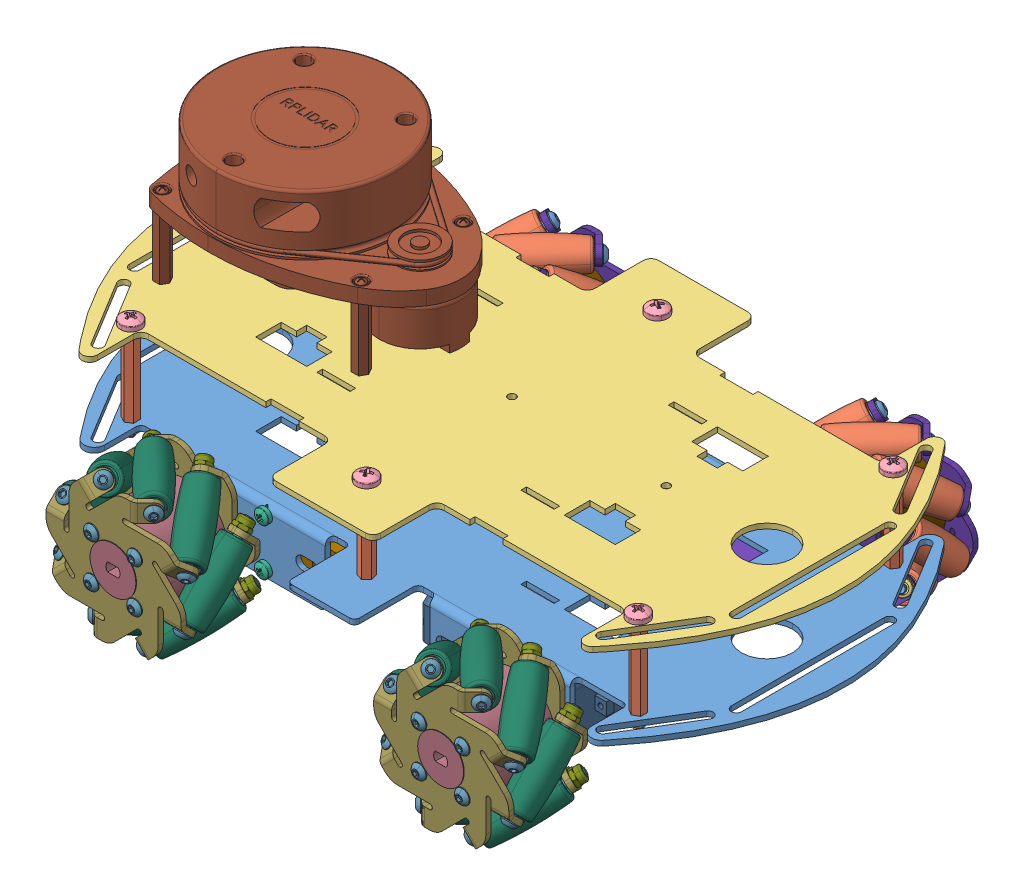
SolidWorks assembly mecanum, configuration Default. Lengths in mm.
Overall size (368.82 154.76 256.48).
187 component instances, 21 part files, 10 mates.
Components (placement in the parent):
- chassis.STEP-1: chassis.STEP [Default] at origin size (318.42 61.29 150)
  - chassis.STEP.STEP-1: chassis.STEP.STEP [Default] at origin size (318.42 61.29 150)
    - bottom chassis.STEP.STEP-1: bottom chassis.STEP.STEP [Default] at (-199.6129 0 0) x (1 0 0) z (0 0 -1) size (314.81 25.02 150)
    - supporting hexagon pillar.STEP.STEP-1: supporting hexagon pillar.STEP.STEP [Default] at (-299.1129 2 50) x (0.997179 0 -0.075054) z (0.075054 0 0.997179) size (4.8 36 5.42)
    - Copy of top chasis^chassis.STEP.STEP-1: Copy of top chasis^chassis.STEP.STEP [Default] at (-199.6129 32 0) size (318.42 2 150)
    - supporting hexagon pillar.STEP.STEP-2: supporting hexagon pillar.STEP.STEP [Default] at (-100.1129 2 50) x (0.482568 0 -0.875858) z (0.875858 0 0.482568) size (4.8 36 5.42)
    - supporting hexagon pillar.STEP.STEP-3: supporting hexagon pillar.STEP.STEP [Default] at (-100.1129 2 -50) x (0.886073 0 -0.463545) z (0.463545 0 0.886073) size (4.8 36 5.42)
    - supporting hexagon pillar.STEP.STEP-4: supporting hexagon pillar.STEP.STEP [Default] at (-299.1129 2 -50) x (0.482568 0 -0.875858) z (0.875858 0 0.482568) size (4.8 36 5.42)
    - pan head cross recess screw_iso_ISO 7045 - M4 x 5 - Z - 5N.STEP.STEP-1: pan head cross recess screw_iso_ISO 7045 - M4 x 5 - Z - 5N.STEP.STEP [Default] at (-100.1129 37.1 -50) x (0 -1 0) z (0.075054 0 0.997179) size (8.02 8 8)
    - pan head cross recess screw_iso_ISO 7045 - M4 x 5 - Z - 5N.STEP.STEP-2: pan head cross recess screw_iso_ISO 7045 - M4 x 5 - Z - 5N.STEP.STEP [Default] at (-100.1129 37.1 50) x (0 -1 0) z (0.075054 0 0.997179) size (8.02 8 8)
    - pan head cross recess screw_iso_ISO 7045 - M4 x 5 - Z - 5N.STEP.STEP-3: pan head cross recess screw_iso_ISO 7045 - M4 x 5 - Z - 5N.STEP.STEP [Default] at (-299.1129 37.1 -50) x (0 -1 0) z (0.075054 0 0.997179) size (8.02 8 8)
    - pan head cross recess screw_iso_ISO 7045 - M4 x 5 - Z - 5N.STEP.STEP-4: pan head cross recess screw_iso_ISO 7045 - M4 x 5 - Z - 5N.STEP.STEP [Default] at (-299.1129 37.1 50) x (0 -1 0) z (0.075054 0 0.997179) size (8.02 8 8)
    - hexagon thin nut (ch)_is_IS 1364-4 - M3-N.STEP.STEP-1: hexagon thin nut (ch)_is_IS 1364-4 - M3-N.STEP.STEP [Default] at (-299.1129 -1.8 -50) x (0.997179 0 -0.075054) z (0 -1 0) size (6.36 6.38 1.82)
    - hexagon thin nut (ch)_is_IS 1364-4 - M3-N.STEP.STEP-2: hexagon thin nut (ch)_is_IS 1364-4 - M3-N.STEP.STEP [Default] at (-299.1129 -1.8 50) x (0.997179 0 -0.075054) z (0 -1 0) size (6.36 6.38 1.82)
    - hexagon thin nut (ch)_is_IS 1364-4 - M3-N.STEP.STEP-3: hexagon thin nut (ch)_is_IS 1364-4 - M3-N.STEP.STEP [Default] at (-100.1129 -1.8 50) x (0.997179 0 -0.075054) z (0 -1 0) size (6.36 6.38 1.82)
    - hexagon thin nut (ch)_is_IS 1364-4 - M3-N.STEP.STEP-4: hexagon thin nut (ch)_is_IS 1364-4 - M3-N.STEP.STEP [Default] at (-100.1129 -1.8 -50) x (0.997179 0 -0.075054) z (0 -1 0) size (6.36 6.38 1.82)
    - pan head cross recess screw_iso_ISO 7045 - M3 x 30 - Z - 30S.STEP.STEP-1: pan head cross recess screw_iso_ISO 7045 - M3 x 30 - Z - 30S.STEP.STEP [Default] at (-155.6129 -20.0527 -55.1366) x (0 0 1) z (-0.913722 -0.40634 0) size (32.35 5.6 5.6)
    - pan head cross recess screw_iso_ISO 7045 - M3 x 30 - Z - 30S.STEP.STEP-2: pan head cross recess screw_iso_ISO 7045 - M3 x 30 - Z - 30S.STEP.STEP [Default] at (-155.6129 -1.6927 -55.1366) x (0 0 1) z (-0.913722 -0.40634 0) size (32.35 5.6 5.6)
    - pan head cross recess screw_iso_ISO 7045 - M3 x 30 - Z - 30S.STEP.STEP-3: pan head cross recess screw_iso_ISO 7045 - M3 x 30 - Z - 30S.STEP.STEP [Default] at (-243.6129 -20.0527 -55.1366) x (0 0 1) z (-0.913722 -0.40634 0) size (32.35 5.6 5.6)
    - pan head cross recess screw_iso_ISO 7045 - M3 x 30 - Z - 30S.STEP.STEP-4: pan head cross recess screw_iso_ISO 7045 - M3 x 30 - Z - 30S.STEP.STEP [Default] at (-243.6129 -1.6927 -55.1366) x (0 0 1) z (-0.913722 -0.40634 0) size (32.35 5.6 5.6)
    - pan head cross recess screw_iso_ISO 7045 - M3 x 30 - Z - 30S.STEP.STEP-5: pan head cross recess screw_iso_ISO 7045 - M3 x 30 - Z - 30S.STEP.STEP [Default] at (-243.6129 -20.0527 55.1366) x (0 0 -1) z (0.924865 -0.380295 0) size (32.35 5.6 5.6)
    - pan head cross recess screw_iso_ISO 7045 - M3 x 30 - Z - 30S.STEP.STEP-6: pan head cross recess screw_iso_ISO 7045 - M3 x 30 - Z - 30S.STEP.STEP [Default] at (-243.6129 -1.6927 55.1366) x (0 0 -1) z (0.924865 -0.380295 0) size (32.35 5.6 5.6)
    - pan head cross recess screw_iso_ISO 7045 - M3 x 30 - Z - 30S.STEP.STEP-7: pan head cross recess screw_iso_ISO 7045 - M3 x 30 - Z - 30S.STEP.STEP [Default] at (-155.6129 -20.0527 55.1366) x (0 0 -1) z (0.924865 -0.380295 0) size (32.35 5.6 5.6)
    - pan head cross recess screw_iso_ISO 7045 - M3 x 30 - Z - 30S.STEP.STEP-8: pan head cross recess screw_iso_ISO 7045 - M3 x 30 - Z - 30S.STEP.STEP [Default] at (-155.6129 -1.6927 55.1366) x (0 0 -1) z (0.924865 -0.380295 0) size (32.35 5.6 5.6)
    - hexagon thin nut (ch)_is_IS 1364-4 - M3-N.STEP.STEP-5: hexagon thin nut (ch)_is_IS 1364-4 - M3-N.STEP.STEP [Default] at (-155.6129 -20.1883 30.4366) x (0.939963 0.341277 0) z (0 0 -1) size (6.36 6.38 1.82)
    - hexagon thin nut (ch)_is_IS 1364-4 - M3-N.STEP.STEP-6: hexagon thin nut (ch)_is_IS 1364-4 - M3-N.STEP.STEP [Default] at (-155.6129 -1.6883 30.4366) x (0.939963 0.341277 0) z (0 0 -1) size (6.36 6.38 1.82)
    - hexagon thin nut (ch)_is_IS 1364-4 - M3-N.STEP.STEP-7: hexagon thin nut (ch)_is_IS 1364-4 - M3-N.STEP.STEP [Default] at (-243.6129 -20.057 30.4366) x (0.939963 0.341277 0) z (0 0 -1) size (6.36 6.38 1.82)
    - hexagon thin nut (ch)_is_IS 1364-4 - M3-N.STEP.STEP-8: hexagon thin nut (ch)_is_IS 1364-4 - M3-N.STEP.STEP [Default] at (-243.6129 -1.557 30.4366) x (0.939963 0.341277 0) z (0 0 -1) size (6.36 6.38 1.82)
    - hexagon thin nut (ch)_is_IS 1364-4 - M3-N.STEP.STEP-9: hexagon thin nut (ch)_is_IS 1364-4 - M3-N.STEP.STEP [Default] at (-243.6129 -20.1883 -30.4366) size (6.36 6.38 1.82)
    - hexagon thin nut (ch)_is_IS 1364-4 - M3-N.STEP.STEP-10: hexagon thin nut (ch)_is_IS 1364-4 - M3-N.STEP.STEP [Default] at (-243.6129 -1.6883 -30.4366) size (6.36 6.38 1.82)
    - hexagon thin nut (ch)_is_IS 1364-4 - M3-N.STEP.STEP-11: hexagon thin nut (ch)_is_IS 1364-4 - M3-N.STEP.STEP [Default] at (-155.6129 -20.057 -30.4366) size (6.36 6.38 1.82)
    - hexagon thin nut (ch)_is_IS 1364-4 - M3-N.STEP.STEP-12: hexagon thin nut (ch)_is_IS 1364-4 - M3-N.STEP.STEP [Default] at (-155.6129 -1.557 -30.4366) size (6.36 6.38 1.82)
    - supporting hexagon pillar.STEP.STEP-5: supporting hexagon pillar.STEP.STEP [Default] at (-199.6129 2 -57) x (0.376997 0 -0.926214) z (0.926214 0 0.376997) size (4.8 36 5.42)
    - supporting hexagon pillar.STEP.STEP-6: supporting hexagon pillar.STEP.STEP [Default] at (-199.6129 2 57) x (-0.715077 0 -0.699046) z (0.699046 0 -0.715077) size (4.8 36 5.42)
    - hexagon thin nut (ch)_is_IS 1364-4 - M3-N.STEP.STEP-13: hexagon thin nut (ch)_is_IS 1364-4 - M3-N.STEP.STEP [Default] at (-199.6129 -1.8 57) x (0.981594 0 -0.190977) z (0 -1 0) size (6.36 6.38 1.82)
    - hexagon thin nut (ch)_is_IS 1364-4 - M3-N.STEP.STEP-14: hexagon thin nut (ch)_is_IS 1364-4 - M3-N.STEP.STEP [Default] at (-199.6129 -1.8 -57) x (0.939935 0 -0.341353) z (0 -1 0) size (6.36 6.38 1.82)
    - pan head cross recess screw_iso_ISO 7045 - M4 x 5 - Z - 5N.STEP.STEP-5: pan head cross recess screw_iso_ISO 7045 - M4 x 5 - Z - 5N.STEP.STEP [Default] at (-199.6129 37.1 -57) x (0 -1 0) z (0.875858 0 0.482568) size (8.02 8 8)
    - pan head cross recess screw_iso_ISO 7045 - M4 x 5 - Z - 5N.STEP.STEP-6: pan head cross recess screw_iso_ISO 7045 - M4 x 5 - Z - 5N.STEP.STEP [Default] at (-199.6129 37.1 57) x (0 -1 0) z (0.463545 0 0.886073) size (8.02 8 8)
  - Motor1.step.STEP-1: Motor1.step.STEP [Default] at (-275.1129 -22.1883 -32.2366) size (66.5 22.5 38.5)
  - Motor2.step.STEP-1: Motor2.step.STEP [Default] at (-124.1129 0.443 -32.2366) x (-1 0 0) z (0 0 1) size (66.5 22.5 38.5)
  - Motor3.step.STEP-1: Motor3.step.STEP [Default] at (-275.1129 0.443 32.2366) x (1 0 0) z (0 0 -1) size (66.5 22.5 38.5)
  - Motor4.step.STEP-1: Motor4.step.STEP [Default] at (-124.1129 -22.1883 32.2366) x (-1 0 0) z (0 0 -1) size (66.5 22.5 38.5)
- rplidarA1.step-1: rplidarA1.step [Default] at (-280.1346 65.1 0.5722) size (96.17 54.6 70)
- left_forward.STEP-1: left_forward.STEP [Default] at (-233.0265 -21.1144 212.4082) x (-0.184533 -0.709257 -0.680369) z (0.944404 -0.319631 0.077057) size (70.26 72.13 71.93)
  - Mirrormecanum wheels.STEP.STEP-1: Mirrormecanum wheels.STEP.STEP [Default] at (81.7182 87.2657 -41.8289) x (0.184533 -0.27212 -0.944404) z (-0.680369 -0.728807 0.077057) size (55.02 55.02 7.58)
  - Mirrorshaft.STEP.STEP-1: Mirrorshaft.STEP.STEP [Default] at (90.9032 97.1046 -42.8692) x (-0.184533 0.27212 0.944404) z (0.680369 0.728807 -0.077057) size (32 32 31.5)
  - Mirrormecanum wheels.STEP.STEP-2: Mirrormecanum wheels.STEP.STEP [Default] at (100.0882 106.9435 -43.9095) x (-0.709257 0.628323 -0.319631) z (0.680369 0.728807 -0.077057) size (55.02 55.02 7.58)
  - Mirrorbolt.STEP.STEP-1: Mirrorbolt.STEP.STEP [Default] at (87.2167 86.0621 -16.0538) x (-0.020427 0.959636 -0.280501) z (0.96794 0.089234 0.234795) size (38.65 5.7 5.7)
  - MirrorRoller.STEP.STEP-1: MirrorRoller.STEP.STEP [Default] at (86.8493 103.3226 -21.099) x (-0.020427 0.959636 -0.280501) z (0.96794 0.089234 0.234795) size (28 12 12)
  - Mirrorbolt.STEP.STEP-2: Mirrorbolt.STEP.STEP [Default] at (86.8189 76.965 -46.8491) x (0.680369 0.728807 -0.077057) z (-0.018616 -0.087924 -0.995953) size (38.65 5.7 5.7)
  - Mirrortorque nut 08_iso_ISO 10511-M3-N.STEP.STEP-1: Mirrortorque nut 08_iso_ISO 10511-M3-N.STEP.STEP [Default] at (110.0875 101.8903 -49.4844) x (-0.185961 0.06998 -0.980062) z (-0.680369 -0.728807 0.077057) size (6.36 6.38 3.91)
  - Mirrortorque nut 08_iso_ISO 10511-M3-N.STEP.STEP-2: Mirrortorque nut 08_iso_ISO 10511-M3-N.STEP.STEP [Default] at (86.1032 120.5687 -26.214) x (0.873571 0.153587 0.461828) z (0.020427 -0.959636 0.280501) size (6.36 6.38 3.91)
  - Mirrorbolt.STEP.STEP-3: Mirrorbolt.STEP.STEP [Default] at (98.9986 73.9021 -27.0356) x (0.034198 0.965566 0.257899) z (0.950888 0.047997 -0.305791) size (38.65 5.7 5.7)
  - Mirrorbolt.STEP.STEP-4: Mirrorbolt.STEP.STEP [Default] at (101.0077 69.945 -46.7228) x (0.350609 0.707763 0.613307) z (0.657996 0.279839 -0.699094) size (38.65 5.7 5.7)
  - Mirrorbolt.STEP.STEP-5: Mirrorbolt.STEP.STEP [Default] at (92.0671 76.5089 -63.5829) x (0.743455 0.337243 0.57753) z (0.260835 0.648951 -0.714722) size (38.65 5.7 5.7)
  - Mirrorbolt.STEP.STEP-6: Mirrorbolt.STEP.STEP [Default] at (77.414 89.7486 -67.7394) x (0.982614 0.071053 0.171526) z (-0.007942 0.939111 -0.343521) size (38.65 5.7 5.7)
  - Mirrorbolt.STEP.STEP-7: Mirrorbolt.STEP.STEP [Default] at (65.632 101.9086 -56.7575) x (0.927989 0.065123 -0.366873) z (0.00911 0.980348 0.197064) size (38.65 5.7 5.7)
  - Mirrorbolt.STEP.STEP-8: Mirrorbolt.STEP.STEP [Default] at (63.6229 105.8657 -37.0704) x (0.611578 0.322927 -0.722281) z (0.302003 0.748506 0.590367) size (38.65 5.7 5.7)
  - Mirrorbolt.STEP.STEP-9: Mirrorbolt.STEP.STEP [Default] at (72.5636 99.3019 -20.2103) x (0.218732 0.693446 -0.686505) z (0.699163 0.379394 0.605995) size (38.65 5.7 5.7)
  - Mirrortorque nut 08_iso_ISO 10511-M3-N.STEP.STEP-3: Mirrortorque nut 08_iso_ISO 10511-M3-N.STEP.STEP [Default] at (99.872 108.6244 -17.6135) x (0.997731 -0.018009 -0.064876) z (-0.034198 -0.965566 -0.257899) size (6.36 6.38 3.91)
  - Mirrortorque nut 08_iso_ISO 10511-M3-N.STEP.STEP-4: Mirrortorque nut 08_iso_ISO 10511-M3-N.STEP.STEP [Default] at (113.3894 95.2906 -24.3739) x (0.804741 0.107283 -0.583851) z (-0.350609 -0.707763 -0.613307) size (6.36 6.38 3.91)
  - Mirrortorque nut 08_iso_ISO 10511-M3-N.STEP.STEP-5: Mirrortorque nut 08_iso_ISO 10511-M3-N.STEP.STEP [Default] at (118.7372 88.378 -42.5352) x (0.407653 0.456068 -0.791089) z (-0.743455 -0.337243 -0.57753) size (6.36 6.38 3.91)
  - Mirrortorque nut 08_iso_ISO 10511-M3-N.STEP.STEP-6: Mirrortorque nut 08_iso_ISO 10511-M3-N.STEP.STEP [Default] at (112.7827 91.936 -61.4588) x (0.039074 0.824034 -0.565191) z (-0.982614 -0.071053 -0.171526) size (6.36 6.38 3.91)
  - Mirrortorque nut 08_iso_ISO 10511-M3-N.STEP.STEP-7: Mirrortorque nut 08_iso_ISO 10511-M3-N.STEP.STEP [Default] at (99.0139 103.8803 -70.0593) x (-0.085085 0.99563 -0.038487) z (-0.927989 -0.065123 0.366873) size (6.36 6.38 3.91)
  - Mirrortorque nut 08_iso_ISO 10511-M3-N.STEP.STEP-8: Mirrortorque nut 08_iso_ISO 10511-M3-N.STEP.STEP [Default] at (85.4965 117.2141 -63.2989) x (0.107904 0.870338 0.480488) z (-0.611578 -0.322927 0.722281) size (6.36 6.38 3.91)
  - Mirrortorque nut 08_iso_ISO 10511-M3-N.STEP.STEP-9: Mirrortorque nut 08_iso_ISO 10511-M3-N.STEP.STEP [Default] at (80.1487 124.1267 -45.1376) x (0.504993 0.521552 0.687725) z (-0.218732 -0.693446 0.686505) size (6.36 6.38 3.91)
  - MirrorRoller.STEP.STEP-2: MirrorRoller.STEP.STEP [Default] at (99.6137 91.2692 -22.3969) x (0.034198 0.965566 0.257899) z (0.950888 0.047997 -0.305791) size (28 12 12)
  - MirrorRoller.STEP.STEP-3: MirrorRoller.STEP.STEP [Default] at (107.3139 82.6752 -35.6916) x (0.350609 0.707763 0.613307) z (0.657996 0.279839 -0.699094) size (28 12 12)
  - MirrorRoller.STEP.STEP-4: MirrorRoller.STEP.STEP [Default] at (105.4392 82.5747 -53.1951) x (0.743455 0.337243 0.57753) z (0.260835 0.648951 -0.714722) size (28 12 12)
  - MirrorRoller.STEP.STEP-5: MirrorRoller.STEP.STEP [Default] at (95.0877 91.0266 -64.6542) x (0.982614 0.071053 0.171526) z (-0.007942 0.939111 -0.343521) size (28 12 12)
  - MirrorRoller.STEP.STEP-6: MirrorRoller.STEP.STEP [Default] at (82.3233 103.0799 -63.3563) x (0.927989 0.065123 -0.366873) z (0.00911 0.980348 0.197064) size (28 12 12)
  - MirrorRoller.STEP.STEP-7: MirrorRoller.STEP.STEP [Default] at (74.6231 111.674 -50.0616) x (0.611578 0.322927 -0.722281) z (0.302003 0.748506 0.590367) size (28 12 12)
  - MirrorRoller.STEP.STEP-8: MirrorRoller.STEP.STEP [Default] at (76.4978 111.7745 -32.5581) x (0.218732 0.693446 -0.686505) z (0.699163 0.379394 0.605995) size (28 12 12)
  - Mirrorbolt.STEP.STEP-10: Mirrorbolt.STEP.STEP [Default] at (83.6873 81.5831 -30.822) x (0.680369 0.728807 -0.077057) z (0.168933 -0.258274 -0.951187) size (38.65 5.7 5.7)
  - Mirrorbolt.STEP.STEP-11: Mirrorbolt.STEP.STEP [Default] at (71.6508 92.2461 -36.2463) x (0.680369 0.728807 -0.077057) z (0.340283 -0.407278 -0.847545) size (38.65 5.7 5.7)
  - Mirrorbolt.STEP.STEP-12: Mirrorbolt.STEP.STEP [Default] at (74.7824 87.6281 -52.2734) x (0.680369 0.728807 -0.077057) z (0.481066 -0.523448 -0.703262) size (38.65 5.7 5.7)
  - Mirrortorque nut 08_iso_ISO 10511-M3-N.STEP.STEP-10: Mirrortorque nut 08_iso_ISO 10511-M3-N.STEP.STEP [Default] at (98.051 112.5533 -54.9087) x (0.533825 -0.420797 0.733458) z (-0.680369 -0.728807 0.077057) size (6.36 6.38 3.91)
  - Mirrortorque nut 08_iso_ISO 10511-M3-N.STEP.STEP-11: Mirrortorque nut 08_iso_ISO 10511-M3-N.STEP.STEP [Default] at (106.9559 106.5083 -33.4573) x (0.321016 -0.201847 0.925314) z (-0.680369 -0.728807 0.077057) size (6.36 6.38 3.91)
  - Mirrortorque nut 08_iso_ISO 10511-M3-N.STEP.STEP-12: Mirrortorque nut 08_iso_ISO 10511-M3-N.STEP.STEP [Default] at (94.9194 117.1713 -38.8817) x (0.017858 0.088626 0.995905) z (-0.680369 -0.728807 0.077057) size (6.36 6.38 3.91)
- right_forward.STEP-1: right_forward.STEP [Default] at (-233.0265 -21.1144 -212.4082) x (-0.184533 -0.709257 0.680369) z (-0.944404 0.319631 0.077057) size (70.26 72.13 71.93)
  - MirrorMirrormecanum wheels.STEP.STEP.STEP-1: MirrorMirrormecanum wheels.STEP.STEP.STEP [Default] at (81.7182 87.2657 41.8289) x (0.184533 -0.27212 0.944404) z (0.680369 0.728807 0.077057) size (55.02 55.02 7.58)
  - MirrorMirrorshaft.STEP.STEP.STEP-1: MirrorMirrorshaft.STEP.STEP.STEP [Default] at (90.9032 97.1046 42.8692) x (-0.184533 0.27212 -0.944404) z (-0.680369 -0.728807 -0.077057) size (32 32 31.5)
  - MirrorMirrormecanum wheels.STEP.STEP.STEP-2: MirrorMirrormecanum wheels.STEP.STEP.STEP [Default] at (100.0882 106.9435 43.9095) x (-0.709257 0.628323 0.319631) z (-0.680369 -0.728807 -0.077057) size (55.02 55.02 7.58)
  - MirrorMirrorbolt.STEP.STEP.STEP-1: MirrorMirrorbolt.STEP.STEP.STEP [Default] at (87.2167 86.0621 16.0538) x (-0.020427 0.959636 0.280501) z (-0.96794 -0.089234 0.234795) size (38.65 5.7 5.7)
  - MirrorMirrorRoller.STEP.STEP.STEP-1: MirrorMirrorRoller.STEP.STEP.STEP [Default] at (86.8493 103.3226 21.099) x (-0.020427 0.959636 0.280501) z (-0.96794 -0.089234 0.234795) size (28 12 12)
  - MirrorMirrorbolt.STEP.STEP.STEP-2: MirrorMirrorbolt.STEP.STEP.STEP [Default] at (86.8189 76.965 46.8491) x (0.680369 0.728807 0.077057) z (0.018616 0.087924 -0.995953) size (38.65 5.7 5.7)
  - MirrorMirrortorque nut 08_iso_ISO 10511-M3-N.STEP.STEP.STEP-1: MirrorMirrortorque nut 08_iso_ISO 10511-M3-N.STEP.STEP.STEP [Default] at (110.0875 101.8903 49.4844) x (-0.185961 0.06998 0.980062) z (0.680369 0.728807 0.077057) size (6.36 6.36 3.91)
  - MirrorMirrortorque nut 08_iso_ISO 10511-M3-N.STEP.STEP.STEP-2: MirrorMirrortorque nut 08_iso_ISO 10511-M3-N.STEP.STEP.STEP [Default] at (86.1032 120.5687 26.214) x (0.873571 0.153587 -0.461828) z (-0.020427 0.959636 0.280501) size (6.36 6.36 3.91)
  - MirrorMirrorbolt.STEP.STEP.STEP-3: MirrorMirrorbolt.STEP.STEP.STEP [Default] at (98.9986 73.9021 27.0356) x (0.034198 0.965566 -0.257899) z (-0.950888 -0.047997 -0.305791) size (38.65 5.7 5.7)
  - MirrorMirrorbolt.STEP.STEP.STEP-4: MirrorMirrorbolt.STEP.STEP.STEP [Default] at (101.0077 69.945 46.7228) x (0.350609 0.707763 -0.613307) z (-0.657996 -0.279839 -0.699094) size (38.65 5.7 5.7)
  - MirrorMirrorbolt.STEP.STEP.STEP-5: MirrorMirrorbolt.STEP.STEP.STEP [Default] at (92.0671 76.5089 63.5829) x (0.743455 0.337243 -0.57753) z (-0.260835 -0.648951 -0.714722) size (38.65 5.7 5.7)
  - MirrorMirrorbolt.STEP.STEP.STEP-6: MirrorMirrorbolt.STEP.STEP.STEP [Default] at (77.414 89.7486 67.7394) x (0.982614 0.071053 -0.171526) z (0.007942 -0.939111 -0.343521) size (38.65 5.7 5.7)
  - MirrorMirrorbolt.STEP.STEP.STEP-7: MirrorMirrorbolt.STEP.STEP.STEP [Default] at (65.632 101.9086 56.7575) x (0.927989 0.065123 0.366873) z (-0.00911 -0.980348 0.197064) size (38.65 5.7 5.7)
  - MirrorMirrorbolt.STEP.STEP.STEP-8: MirrorMirrorbolt.STEP.STEP.STEP [Default] at (63.6229 105.8657 37.0704) x (0.611578 0.322927 0.722281) z (-0.302003 -0.748506 0.590367) size (38.65 5.7 5.7)
  - MirrorMirrorbolt.STEP.STEP.STEP-9: MirrorMirrorbolt.STEP.STEP.STEP [Default] at (72.5636 99.3019 20.2103) x (0.218732 0.693446 0.686505) z (-0.699163 -0.379394 0.605995) size (38.65 5.7 5.7)
  - MirrorMirrortorque nut 08_iso_ISO 10511-M3-N.STEP.STEP.STEP-3: MirrorMirrortorque nut 08_iso_ISO 10511-M3-N.STEP.STEP.STEP [Default] at (99.872 108.6244 17.6135) x (0.997731 -0.018009 0.064876) z (0.034198 0.965566 -0.257899) size (6.36 6.36 3.91)
  - MirrorMirrortorque nut 08_iso_ISO 10511-M3-N.STEP.STEP.STEP-4: MirrorMirrortorque nut 08_iso_ISO 10511-M3-N.STEP.STEP.STEP [Default] at (113.3894 95.2906 24.3739) x (0.804741 0.107283 0.583851) z (0.350609 0.707763 -0.613307) size (6.36 6.36 3.91)
  - MirrorMirrortorque nut 08_iso_ISO 10511-M3-N.STEP.STEP.STEP-5: MirrorMirrortorque nut 08_iso_ISO 10511-M3-N.STEP.STEP.STEP [Default] at (118.7372 88.378 42.5352) x (0.407653 0.456068 0.791089) z (0.743455 0.337243 -0.57753) size (6.36 6.36 3.91)
  - MirrorMirrortorque nut 08_iso_ISO 10511-M3-N.STEP.STEP.STEP-6: MirrorMirrortorque nut 08_iso_ISO 10511-M3-N.STEP.STEP.STEP [Default] at (112.7827 91.936 61.4588) x (0.039074 0.824034 0.565191) z (0.982614 0.071053 -0.171526) size (6.36 6.36 3.91)
  - MirrorMirrortorque nut 08_iso_ISO 10511-M3-N.STEP.STEP.STEP-7: MirrorMirrortorque nut 08_iso_ISO 10511-M3-N.STEP.STEP.STEP [Default] at (99.0139 103.8803 70.0593) x (-0.085085 0.99563 0.038487) z (0.927989 0.065123 0.366873) size (6.36 6.36 3.91)
  - MirrorMirrortorque nut 08_iso_ISO 10511-M3-N.STEP.STEP.STEP-8: MirrorMirrortorque nut 08_iso_ISO 10511-M3-N.STEP.STEP.STEP [Default] at (85.4965 117.2141 63.2989) x (0.107904 0.870338 -0.480488) z (0.611578 0.322927 0.722281) size (6.36 6.36 3.91)
  - MirrorMirrortorque nut 08_iso_ISO 10511-M3-N.STEP.STEP.STEP-9: MirrorMirrortorque nut 08_iso_ISO 10511-M3-N.STEP.STEP.STEP [Default] at (80.1487 124.1267 45.1376) x (0.504993 0.521552 -0.687725) z (0.218732 0.693446 0.686505) size (6.36 6.36 3.91)
  - MirrorMirrorRoller.STEP.STEP.STEP-2: MirrorMirrorRoller.STEP.STEP.STEP [Default] at (99.6137 91.2692 22.3969) x (0.034198 0.965566 -0.257899) z (-0.950888 -0.047997 -0.305791) size (28 12 12)
  - MirrorMirrorRoller.STEP.STEP.STEP-3: MirrorMirrorRoller.STEP.STEP.STEP [Default] at (107.3139 82.6752 35.6916) x (0.350609 0.707763 -0.613307) z (-0.657996 -0.279839 -0.699094) size (28 12 12)
  - MirrorMirrorRoller.STEP.STEP.STEP-4: MirrorMirrorRoller.STEP.STEP.STEP [Default] at (105.4392 82.5747 53.1951) x (0.743455 0.337243 -0.57753) z (-0.260835 -0.648951 -0.714722) size (28 12 12)
  - MirrorMirrorRoller.STEP.STEP.STEP-5: MirrorMirrorRoller.STEP.STEP.STEP [Default] at (95.0877 91.0266 64.6542) x (0.982614 0.071053 -0.171526) z (0.007942 -0.939111 -0.343521) size (28 12 12)
  - MirrorMirrorRoller.STEP.STEP.STEP-6: MirrorMirrorRoller.STEP.STEP.STEP [Default] at (82.3233 103.0799 63.3563) x (0.927989 0.065123 0.366873) z (-0.00911 -0.980348 0.197064) size (28 12 12)
  - MirrorMirrorRoller.STEP.STEP.STEP-7: MirrorMirrorRoller.STEP.STEP.STEP [Default] at (74.6231 111.674 50.0616) x (0.611578 0.322927 0.722281) z (-0.302003 -0.748506 0.590367) size (28 12 12)
  - MirrorMirrorRoller.STEP.STEP.STEP-8: MirrorMirrorRoller.STEP.STEP.STEP [Default] at (76.4978 111.7745 32.5581) x (0.218732 0.693446 0.686505) z (-0.699163 -0.379394 0.605995) size (28 12 12)
  - MirrorMirrorbolt.STEP.STEP.STEP-10: MirrorMirrorbolt.STEP.STEP.STEP [Default] at (83.6873 81.5831 30.822) x (0.680369 0.728807 0.077057) z (-0.168933 0.258274 -0.951187) size (38.65 5.7 5.7)
  - MirrorMirrorbolt.STEP.STEP.STEP-11: MirrorMirrorbolt.STEP.STEP.STEP [Default] at (71.6508 92.2461 36.2463) x (0.680369 0.728807 0.077057) z (-0.340283 0.407278 -0.847545) size (38.65 5.7 5.7)
  - MirrorMirrorbolt.STEP.STEP.STEP-12: MirrorMirrorbolt.STEP.STEP.STEP [Default] at (74.7824 87.6281 52.2734) x (0.680369 0.728807 0.077057) z (-0.481066 0.523448 -0.703262) size (38.65 5.7 5.7)
  - MirrorMirrortorque nut 08_iso_ISO 10511-M3-N.STEP.STEP.STEP-10: MirrorMirrortorque nut 08_iso_ISO 10511-M3-N.STEP.STEP.STEP [Default] at (98.051 112.5533 54.9087) x (0.533825 -0.420797 -0.733458) z (0.680369 0.728807 0.077057) size (6.36 6.36 3.91)
  - MirrorMirrortorque nut 08_iso_ISO 10511-M3-N.STEP.STEP.STEP-11: MirrorMirrortorque nut 08_iso_ISO 10511-M3-N.STEP.STEP.STEP [Default] at (106.9559 106.5083 33.4573) x (0.321016 -0.201847 -0.925314) z (0.680369 0.728807 0.077057) size (6.36 6.36 3.91)
  - MirrorMirrortorque nut 08_iso_ISO 10511-M3-N.STEP.STEP.STEP-12: MirrorMirrortorque nut 08_iso_ISO 10511-M3-N.STEP.STEP.STEP [Default] at (94.9194 117.1713 38.8817) x (0.017858 0.088626 -0.995905) z (0.680369 0.728807 0.077057) size (6.36 6.36 3.91)
- left_back.STEP-1: left_back.STEP [Default] at (-104.5265 -21.1144 212.4082) x (-0.184533 -0.709257 -0.680369) z (0.944404 -0.319631 0.077057) size (70.26 72.13 71.93)
  - Mirrormecanum wheels.STEP.STEP-1: Mirrormecanum wheels.STEP.STEP [Default] at (81.7182 87.2657 -41.8289) x (0.184533 -0.27212 -0.944404) z (-0.680369 -0.728807 0.077057) size (55.02 55.02 7.58)
  - Mirrorshaft.STEP.STEP-1: Mirrorshaft.STEP.STEP [Default] at (90.9032 97.1046 -42.8692) x (-0.184533 0.27212 0.944404) z (0.680369 0.728807 -0.077057) size (32 32 31.5)
  - Mirrormecanum wheels.STEP.STEP-2: Mirrormecanum wheels.STEP.STEP [Default] at (100.0882 106.9435 -43.9095) x (-0.709257 0.628323 -0.319631) z (0.680369 0.728807 -0.077057) size (55.02 55.02 7.58)
  - Mirrorbolt.STEP.STEP-1: Mirrorbolt.STEP.STEP [Default] at (87.2167 86.0621 -16.0538) x (-0.020427 0.959636 -0.280501) z (0.96794 0.089234 0.234795) size (38.65 5.7 5.7)
  - MirrorRoller.STEP.STEP-1: MirrorRoller.STEP.STEP [Default] at (86.8493 103.3226 -21.099) x (-0.020427 0.959636 -0.280501) z (0.96794 0.089234 0.234795) size (28 12 12)
  - Mirrorbolt.STEP.STEP-2: Mirrorbolt.STEP.STEP [Default] at (86.8189 76.965 -46.8491) x (0.680369 0.728807 -0.077057) z (-0.018616 -0.087924 -0.995953) size (38.65 5.7 5.7)
  - Mirrortorque nut 08_iso_ISO 10511-M3-N.STEP.STEP-1: Mirrortorque nut 08_iso_ISO 10511-M3-N.STEP.STEP [Default] at (110.0875 101.8903 -49.4844) x (-0.185961 0.06998 -0.980062) z (-0.680369 -0.728807 0.077057) size (6.36 6.38 3.91)
  - Mirrortorque nut 08_iso_ISO 10511-M3-N.STEP.STEP-2: Mirrortorque nut 08_iso_ISO 10511-M3-N.STEP.STEP [Default] at (86.1032 120.5687 -26.214) x (0.873571 0.153587 0.461828) z (0.020427 -0.959636 0.280501) size (6.36 6.38 3.91)
  - Mirrorbolt.STEP.STEP-3: Mirrorbolt.STEP.STEP [Default] at (98.9986 73.9021 -27.0356) x (0.034198 0.965566 0.257899) z (0.950888 0.047997 -0.305791) size (38.65 5.7 5.7)
  - Mirrorbolt.STEP.STEP-4: Mirrorbolt.STEP.STEP [Default] at (101.0077 69.945 -46.7228) x (0.350609 0.707763 0.613307) z (0.657996 0.279839 -0.699094) size (38.65 5.7 5.7)
  - Mirrorbolt.STEP.STEP-5: Mirrorbolt.STEP.STEP [Default] at (92.0671 76.5089 -63.5829) x (0.743455 0.337243 0.57753) z (0.260835 0.648951 -0.714722) size (38.65 5.7 5.7)
  - Mirrorbolt.STEP.STEP-6: Mirrorbolt.STEP.STEP [Default] at (77.414 89.7486 -67.7394) x (0.982614 0.071053 0.171526) z (-0.007942 0.939111 -0.343521) size (38.65 5.7 5.7)
  - Mirrorbolt.STEP.STEP-7: Mirrorbolt.STEP.STEP [Default] at (65.632 101.9086 -56.7575) x (0.927989 0.065123 -0.366873) z (0.00911 0.980348 0.197064) size (38.65 5.7 5.7)
  - Mirrorbolt.STEP.STEP-8: Mirrorbolt.STEP.STEP [Default] at (63.6229 105.8657 -37.0704) x (0.611578 0.322927 -0.722281) z (0.302003 0.748506 0.590367) size (38.65 5.7 5.7)
  - Mirrorbolt.STEP.STEP-9: Mirrorbolt.STEP.STEP [Default] at (72.5636 99.3019 -20.2103) x (0.218732 0.693446 -0.686505) z (0.699163 0.379394 0.605995) size (38.65 5.7 5.7)
  - Mirrortorque nut 08_iso_ISO 10511-M3-N.STEP.STEP-3: Mirrortorque nut 08_iso_ISO 10511-M3-N.STEP.STEP [Default] at (99.872 108.6244 -17.6135) x (0.997731 -0.018009 -0.064876) z (-0.034198 -0.965566 -0.257899) size (6.36 6.38 3.91)
  - Mirrortorque nut 08_iso_ISO 10511-M3-N.STEP.STEP-4: Mirrortorque nut 08_iso_ISO 10511-M3-N.STEP.STEP [Default] at (113.3894 95.2906 -24.3739) x (0.804741 0.107283 -0.583851) z (-0.350609 -0.707763 -0.613307) size (6.36 6.38 3.91)
  - Mirrortorque nut 08_iso_ISO 10511-M3-N.STEP.STEP-5: Mirrortorque nut 08_iso_ISO 10511-M3-N.STEP.STEP [Default] at (118.7372 88.378 -42.5352) x (0.407653 0.456068 -0.791089) z (-0.743455 -0.337243 -0.57753) size (6.36 6.38 3.91)
  - Mirrortorque nut 08_iso_ISO 10511-M3-N.STEP.STEP-6: Mirrortorque nut 08_iso_ISO 10511-M3-N.STEP.STEP [Default] at (112.7827 91.936 -61.4588) x (0.039074 0.824034 -0.565191) z (-0.982614 -0.071053 -0.171526) size (6.36 6.38 3.91)
  - Mirrortorque nut 08_iso_ISO 10511-M3-N.STEP.STEP-7: Mirrortorque nut 08_iso_ISO 10511-M3-N.STEP.STEP [Default] at (99.0139 103.8803 -70.0593) x (-0.085085 0.99563 -0.038487) z (-0.927989 -0.065123 0.366873) size (6.36 6.38 3.91)
  - Mirrortorque nut 08_iso_ISO 10511-M3-N.STEP.STEP-8: Mirrortorque nut 08_iso_ISO 10511-M3-N.STEP.STEP [Default] at (85.4965 117.2141 -63.2989) x (0.107904 0.870338 0.480488) z (-0.611578 -0.322927 0.722281) size (6.36 6.38 3.91)
  - Mirrortorque nut 08_iso_ISO 10511-M3-N.STEP.STEP-9: Mirrortorque nut 08_iso_ISO 10511-M3-N.STEP.STEP [Default] at (80.1487 124.1267 -45.1376) x (0.504993 0.521552 0.687725) z (-0.218732 -0.693446 0.686505) size (6.36 6.38 3.91)
  - MirrorRoller.STEP.STEP-2: MirrorRoller.STEP.STEP [Default] at (99.6137 91.2692 -22.3969) x (0.034198 0.965566 0.257899) z (0.950888 0.047997 -0.305791) size (28 12 12)
  - MirrorRoller.STEP.STEP-3: MirrorRoller.STEP.STEP [Default] at (107.3139 82.6752 -35.6916) x (0.350609 0.707763 0.613307) z (0.657996 0.279839 -0.699094) size (28 12 12)
  - MirrorRoller.STEP.STEP-4: MirrorRoller.STEP.STEP [Default] at (105.4392 82.5747 -53.1951) x (0.743455 0.337243 0.57753) z (0.260835 0.648951 -0.714722) size (28 12 12)
  - MirrorRoller.STEP.STEP-5: MirrorRoller.STEP.STEP [Default] at (95.0877 91.0266 -64.6542) x (0.982614 0.071053 0.171526) z (-0.007942 0.939111 -0.343521) size (28 12 12)
  - MirrorRoller.STEP.STEP-6: MirrorRoller.STEP.STEP [Default] at (82.3233 103.0799 -63.3563) x (0.927989 0.065123 -0.366873) z (0.00911 0.980348 0.197064) size (28 12 12)
  - MirrorRoller.STEP.STEP-7: MirrorRoller.STEP.STEP [Default] at (74.6231 111.674 -50.0616) x (0.611578 0.322927 -0.722281) z (0.302003 0.748506 0.590367) size (28 12 12)
  - MirrorRoller.STEP.STEP-8: MirrorRoller.STEP.STEP [Default] at (76.4978 111.7745 -32.5581) x (0.218732 0.693446 -0.686505) z (0.699163 0.379394 0.605995) size (28 12 12)
  - Mirrorbolt.STEP.STEP-10: Mirrorbolt.STEP.STEP [Default] at (83.6873 81.5831 -30.822) x (0.680369 0.728807 -0.077057) z (0.168933 -0.258274 -0.951187) size (38.65 5.7 5.7)
  - Mirrorbolt.STEP.STEP-11: Mirrorbolt.STEP.STEP [Default] at (71.6508 92.2461 -36.2463) x (0.680369 0.728807 -0.077057) z (0.340283 -0.407278 -0.847545) size (38.65 5.7 5.7)
  - Mirrorbolt.STEP.STEP-12: Mirrorbolt.STEP.STEP [Default] at (74.7824 87.6281 -52.2734) x (0.680369 0.728807 -0.077057) z (0.481066 -0.523448 -0.703262) size (38.65 5.7 5.7)
  - Mirrortorque nut 08_iso_ISO 10511-M3-N.STEP.STEP-10: Mirrortorque nut 08_iso_ISO 10511-M3-N.STEP.STEP [Default] at (98.051 112.5533 -54.9087) x (0.533825 -0.420797 0.733458) z (-0.680369 -0.728807 0.077057) size (6.36 6.38 3.91)
  - Mirrortorque nut 08_iso_ISO 10511-M3-N.STEP.STEP-11: Mirrortorque nut 08_iso_ISO 10511-M3-N.STEP.STEP [Default] at (106.9559 106.5083 -33.4573) x (0.321016 -0.201847 0.925314) z (-0.680369 -0.728807 0.077057) size (6.36 6.38 3.91)
  - Mirrortorque nut 08_iso_ISO 10511-M3-N.STEP.STEP-12: Mirrortorque nut 08_iso_ISO 10511-M3-N.STEP.STEP [Default] at (94.9194 117.1713 -38.8817) x (0.017858 0.088626 0.995905) z (-0.680369 -0.728807 0.077057) size (6.36 6.38 3.91)
- right_back.STEP-1: right_back.STEP [Default] at (-104.5265 -21.1144 -212.4082) x (-0.184533 -0.709257 0.680369) z (-0.944404 0.319631 0.077057) size (70.26 72.13 71.93)
  - MirrorMirrormecanum wheels.STEP.STEP.STEP-1: MirrorMirrormecanum wheels.STEP.STEP.STEP [Default] at (81.7182 87.2657 41.8289) x (0.184533 -0.27212 0.944404) z (0.680369 0.728807 0.077057) size (55.02 55.02 7.58)
  - MirrorMirrorshaft.STEP.STEP.STEP-1: MirrorMirrorshaft.STEP.STEP.STEP [Default] at (90.9032 97.1046 42.8692) x (-0.184533 0.27212 -0.944404) z (-0.680369 -0.728807 -0.077057) size (32 32 31.5)
  - MirrorMirrormecanum wheels.STEP.STEP.STEP-2: MirrorMirrormecanum wheels.STEP.STEP.STEP [Default] at (100.0882 106.9435 43.9095) x (-0.709257 0.628323 0.319631) z (-0.680369 -0.728807 -0.077057) size (55.02 55.02 7.58)
  - MirrorMirrorbolt.STEP.STEP.STEP-1: MirrorMirrorbolt.STEP.STEP.STEP [Default] at (87.2167 86.0621 16.0538) x (-0.020427 0.959636 0.280501) z (-0.96794 -0.089234 0.234795) size (38.65 5.7 5.7)
  - MirrorMirrorRoller.STEP.STEP.STEP-1: MirrorMirrorRoller.STEP.STEP.STEP [Default] at (86.8493 103.3226 21.099) x (-0.020427 0.959636 0.280501) z (-0.96794 -0.089234 0.234795) size (28 12 12)
  - MirrorMirrorbolt.STEP.STEP.STEP-2: MirrorMirrorbolt.STEP.STEP.STEP [Default] at (86.8189 76.965 46.8491) x (0.680369 0.728807 0.077057) z (0.018616 0.087924 -0.995953) size (38.65 5.7 5.7)
  - MirrorMirrortorque nut 08_iso_ISO 10511-M3-N.STEP.STEP.STEP-1: MirrorMirrortorque nut 08_iso_ISO 10511-M3-N.STEP.STEP.STEP [Default] at (110.0875 101.8903 49.4844) x (-0.185961 0.06998 0.980062) z (0.680369 0.728807 0.077057) size (6.36 6.36 3.91)
  - MirrorMirrortorque nut 08_iso_ISO 10511-M3-N.STEP.STEP.STEP-2: MirrorMirrortorque nut 08_iso_ISO 10511-M3-N.STEP.STEP.STEP [Default] at (86.1032 120.5687 26.214) x (0.873571 0.153587 -0.461828) z (-0.020427 0.959636 0.280501) size (6.36 6.36 3.91)
  - MirrorMirrorbolt.STEP.STEP.STEP-3: MirrorMirrorbolt.STEP.STEP.STEP [Default] at (98.9986 73.9021 27.0356) x (0.034198 0.965566 -0.257899) z (-0.950888 -0.047997 -0.305791) size (38.65 5.7 5.7)
  - MirrorMirrorbolt.STEP.STEP.STEP-4: MirrorMirrorbolt.STEP.STEP.STEP [Default] at (101.0077 69.945 46.7228) x (0.350609 0.707763 -0.613307) z (-0.657996 -0.279839 -0.699094) size (38.65 5.7 5.7)
  - MirrorMirrorbolt.STEP.STEP.STEP-5: MirrorMirrorbolt.STEP.STEP.STEP [Default] at (92.0671 76.5089 63.5829) x (0.743455 0.337243 -0.57753) z (-0.260835 -0.648951 -0.714722) size (38.65 5.7 5.7)
  - MirrorMirrorbolt.STEP.STEP.STEP-6: MirrorMirrorbolt.STEP.STEP.STEP [Default] at (77.414 89.7486 67.7394) x (0.982614 0.071053 -0.171526) z (0.007942 -0.939111 -0.343521) size (38.65 5.7 5.7)
  - MirrorMirrorbolt.STEP.STEP.STEP-7: MirrorMirrorbolt.STEP.STEP.STEP [Default] at (65.632 101.9086 56.7575) x (0.927989 0.065123 0.366873) z (-0.00911 -0.980348 0.197064) size (38.65 5.7 5.7)
  - MirrorMirrorbolt.STEP.STEP.STEP-8: MirrorMirrorbolt.STEP.STEP.STEP [Default] at (63.6229 105.8657 37.0704) x (0.611578 0.322927 0.722281) z (-0.302003 -0.748506 0.590367) size (38.65 5.7 5.7)
  - MirrorMirrorbolt.STEP.STEP.STEP-9: MirrorMirrorbolt.STEP.STEP.STEP [Default] at (72.5636 99.3019 20.2103) x (0.218732 0.693446 0.686505) z (-0.699163 -0.379394 0.605995) size (38.65 5.7 5.7)
  - MirrorMirrortorque nut 08_iso_ISO 10511-M3-N.STEP.STEP.STEP-3: MirrorMirrortorque nut 08_iso_ISO 10511-M3-N.STEP.STEP.STEP [Default] at (99.872 108.6244 17.6135) x (0.997731 -0.018009 0.064876) z (0.034198 0.965566 -0.257899) size (6.36 6.36 3.91)
  - MirrorMirrortorque nut 08_iso_ISO 10511-M3-N.STEP.STEP.STEP-4: MirrorMirrortorque nut 08_iso_ISO 10511-M3-N.STEP.STEP.STEP [Default] at (113.3894 95.2906 24.3739) x (0.804741 0.107283 0.583851) z (0.350609 0.707763 -0.613307) size (6.36 6.36 3.91)
  - MirrorMirrortorque nut 08_iso_ISO 10511-M3-N.STEP.STEP.STEP-5: MirrorMirrortorque nut 08_iso_ISO 10511-M3-N.STEP.STEP.STEP [Default] at (118.7372 88.378 42.5352) x (0.407653 0.456068 0.791089) z (0.743455 0.337243 -0.57753) size (6.36 6.36 3.91)
  - MirrorMirrortorque nut 08_iso_ISO 10511-M3-N.STEP.STEP.STEP-6: MirrorMirrortorque nut 08_iso_ISO 10511-M3-N.STEP.STEP.STEP [Default] at (112.7827 91.936 61.4588) x (0.039074 0.824034 0.565191) z (0.982614 0.071053 -0.171526) size (6.36 6.36 3.91)
  - MirrorMirrortorque nut 08_iso_ISO 10511-M3-N.STEP.STEP.STEP-7: MirrorMirrortorque nut 08_iso_ISO 10511-M3-N.STEP.STEP.STEP [Default] at (99.0139 103.8803 70.0593) x (-0.085085 0.99563 0.038487) z (0.927989 0.065123 0.366873) size (6.36 6.36 3.91)
  - MirrorMirrortorque nut 08_iso_ISO 10511-M3-N.STEP.STEP.STEP-8: MirrorMirrortorque nut 08_iso_ISO 10511-M3-N.STEP.STEP.STEP [Default] at (85.4965 117.2141 63.2989) x (0.107904 0.870338 -0.480488) z (0.611578 0.322927 0.722281) size (6.36 6.36 3.91)
  - MirrorMirrortorque nut 08_iso_ISO 10511-M3-N.STEP.STEP.STEP-9: MirrorMirrortorque nut 08_iso_ISO 10511-M3-N.STEP.STEP.STEP [Default] at (80.1487 124.1267 45.1376) x (0.504993 0.521552 -0.687725) z (0.218732 0.693446 0.686505) size (6.36 6.36 3.91)
  - MirrorMirrorRoller.STEP.STEP.STEP-2: MirrorMirrorRoller.STEP.STEP.STEP [Default] at (99.6137 91.2692 22.3969) x (0.034198 0.965566 -0.257899) z (-0.950888 -0.047997 -0.305791) size (28 12 12)
  - MirrorMirrorRoller.STEP.STEP.STEP-3: MirrorMirrorRoller.STEP.STEP.STEP [Default] at (107.3139 82.6752 35.6916) x (0.350609 0.707763 -0.613307) z (-0.657996 -0.279839 -0.699094) size (28 12 12)
  - MirrorMirrorRoller.STEP.STEP.STEP-4: MirrorMirrorRoller.STEP.STEP.STEP [Default] at (105.4392 82.5747 53.1951) x (0.743455 0.337243 -0.57753) z (-0.260835 -0.648951 -0.714722) size (28 12 12)
  - MirrorMirrorRoller.STEP.STEP.STEP-5: MirrorMirrorRoller.STEP.STEP.STEP [Default] at (95.0877 91.0266 64.6542) x (0.982614 0.071053 -0.171526) z (0.007942 -0.939111 -0.343521) size (28 12 12)
  - MirrorMirrorRoller.STEP.STEP.STEP-6: MirrorMirrorRoller.STEP.STEP.STEP [Default] at (82.3233 103.0799 63.3563) x (0.927989 0.065123 0.366873) z (-0.00911 -0.980348 0.197064) size (28 12 12)
  - MirrorMirrorRoller.STEP.STEP.STEP-7: MirrorMirrorRoller.STEP.STEP.STEP [Default] at (74.6231 111.674 50.0616) x (0.611578 0.322927 0.722281) z (-0.302003 -0.748506 0.590367) size (28 12 12)
  - MirrorMirrorRoller.STEP.STEP.STEP-8: MirrorMirrorRoller.STEP.STEP.STEP [Default] at (76.4978 111.7745 32.5581) x (0.218732 0.693446 0.686505) z (-0.699163 -0.379394 0.605995) size (28 12 12)
  - MirrorMirrorbolt.STEP.STEP.STEP-10: MirrorMirrorbolt.STEP.STEP.STEP [Default] at (83.6873 81.5831 30.822) x (0.680369 0.728807 0.077057) z (-0.168933 0.258274 -0.951187) size (38.65 5.7 5.7)
  - MirrorMirrorbolt.STEP.STEP.STEP-11: MirrorMirrorbolt.STEP.STEP.STEP [Default] at (71.6508 92.2461 36.2463) x (0.680369 0.728807 0.077057) z (-0.340283 0.407278 -0.847545) size (38.65 5.7 5.7)
  - MirrorMirrorbolt.STEP.STEP.STEP-12: MirrorMirrorbolt.STEP.STEP.STEP [Default] at (74.7824 87.6281 52.2734) x (0.680369 0.728807 0.077057) z (-0.481066 0.523448 -0.703262) size (38.65 5.7 5.7)
  - MirrorMirrortorque nut 08_iso_ISO 10511-M3-N.STEP.STEP.STEP-10: MirrorMirrortorque nut 08_iso_ISO 10511-M3-N.STEP.STEP.STEP [Default] at (98.051 112.5533 54.9087) x (0.533825 -0.420797 -0.733458) z (0.680369 0.728807 0.077057) size (6.36 6.36 3.91)
  - MirrorMirrortorque nut 08_iso_ISO 10511-M3-N.STEP.STEP.STEP-11: MirrorMirrortorque nut 08_iso_ISO 10511-M3-N.STEP.STEP.STEP [Default] at (106.9559 106.5083 33.4573) x (0.321016 -0.201847 -0.925314) z (0.680369 0.728807 0.077057) size (6.36 6.36 3.91)
  - MirrorMirrortorque nut 08_iso_ISO 10511-M3-N.STEP.STEP.STEP-12: MirrorMirrortorque nut 08_iso_ISO 10511-M3-N.STEP.STEP.STEP [Default] at (94.9194 117.1713 38.8817) x (0.017858 0.088626 -0.995905) z (0.680369 0.728807 0.077057) size (6.36 6.36 3.91)
Mates (geometry in assembly coordinates):
- Coincident1: coincident anti-aligned: plane of chassis.STEP-1/chassis.STEP.STEP-1/Copy of top chasis^chassis.STEP.STEP-1 through (-199.6129 34 0) normal (0 1 0); plane of rplidarA1.step-1 through (-280.1346 34 0.5722) normal (0 -1 0)
- Concentric2: concentric anti-aligned: cylinder of chassis.STEP-1/Motor3.step.STEP-1 through (-263.8629 -10.8727 60.7366) axis (0 0 -1) radius 2.75; cylinder of left_forward.STEP-1/Mirrorshaft.STEP.STEP-1 through (-263.8629 -10.8727 39.5234) axis (0 0 1) radius 2.75
- Distance3: distance = 8 mm anti-aligned: plane of chassis.STEP-1/chassis.STEP.STEP-1/bottom chassis.STEP.STEP-1 through (-329.6129 51.9912 52.7366) normal (0 0 1); plane of left_forward.STEP-1/Mirrorshaft.STEP.STEP-1 through (-263.8629 -10.8727 60.7366) normal (0 0 -1)
- Parallel3: parallel anti-aligned: cylinder of chassis.STEP-1/Motor1.step.STEP-1 through (-263.8629 -10.8727 -60.7366) axis (0 0 1) radius 2.75; cylinder of right_forward.STEP-1/MirrorMirrorshaft.STEP.STEP.STEP-1 through (-263.8629 -10.8727 -39.5234) axis (0 0 -1) radius 2.75
- Concentric4: concentric anti-aligned: cylinder of chassis.STEP-1/Motor1.step.STEP-1 through (-263.8629 -10.8727 -60.7366) axis (0 0 1) radius 2.75; cylinder of right_forward.STEP-1/MirrorMirrorshaft.STEP.STEP.STEP-1 through (-263.8629 -10.8727 -39.5234) axis (0 0 -1) radius 2.75
- Distance5: distance = 8 mm anti-aligned: plane of chassis.STEP-1/chassis.STEP.STEP-1/bottom chassis.STEP.STEP-1 through (-329.6129 51.9912 -52.7366) normal (0 0 -1); plane of right_forward.STEP-1/MirrorMirrorshaft.STEP.STEP.STEP-1 through (-263.8629 -10.8727 -60.7366) normal (0 0 1)
- Concentric5: concentric anti-aligned: cylinder of chassis.STEP-1/Motor4.step.STEP-1 through (-135.3629 -10.8727 60.7366) axis (0 0 -1) radius 2.75; cylinder of left_back.STEP-1/Mirrorshaft.STEP.STEP-1 through (-135.3629 -10.8727 39.5234) axis (0 0 1) radius 2.75
- Distance7: distance = 8 mm anti-aligned: plane of chassis.STEP-1/chassis.STEP.STEP-1/bottom chassis.STEP.STEP-1 through (-329.6129 51.9912 52.7366) normal (0 0 1); plane of left_back.STEP-1/Mirrorshaft.STEP.STEP-1 through (-135.3629 -10.8727 60.7366) normal (0 0 -1)
- Concentric6: concentric anti-aligned: cylinder of chassis.STEP-1/Motor2.step.STEP-1 through (-135.3629 -10.8727 -60.7366) axis (0 0 1) radius 2.75; cylinder of right_back.STEP-1/MirrorMirrorshaft.STEP.STEP.STEP-1 through (-135.3629 -10.8727 -39.5234) axis (0 0 -1) radius 2.75
- Distance9: distance = 8 mm anti-aligned: plane of chassis.STEP-1/chassis.STEP.STEP-1/bottom chassis.STEP.STEP-1 through (-329.6129 51.9912 -52.7366) normal (0 0 -1); plane of right_back.STEP-1/MirrorMirrorshaft.STEP.STEP.STEP-1 through (-135.3629 -10.8727 -60.7366) normal (0 0 1)
